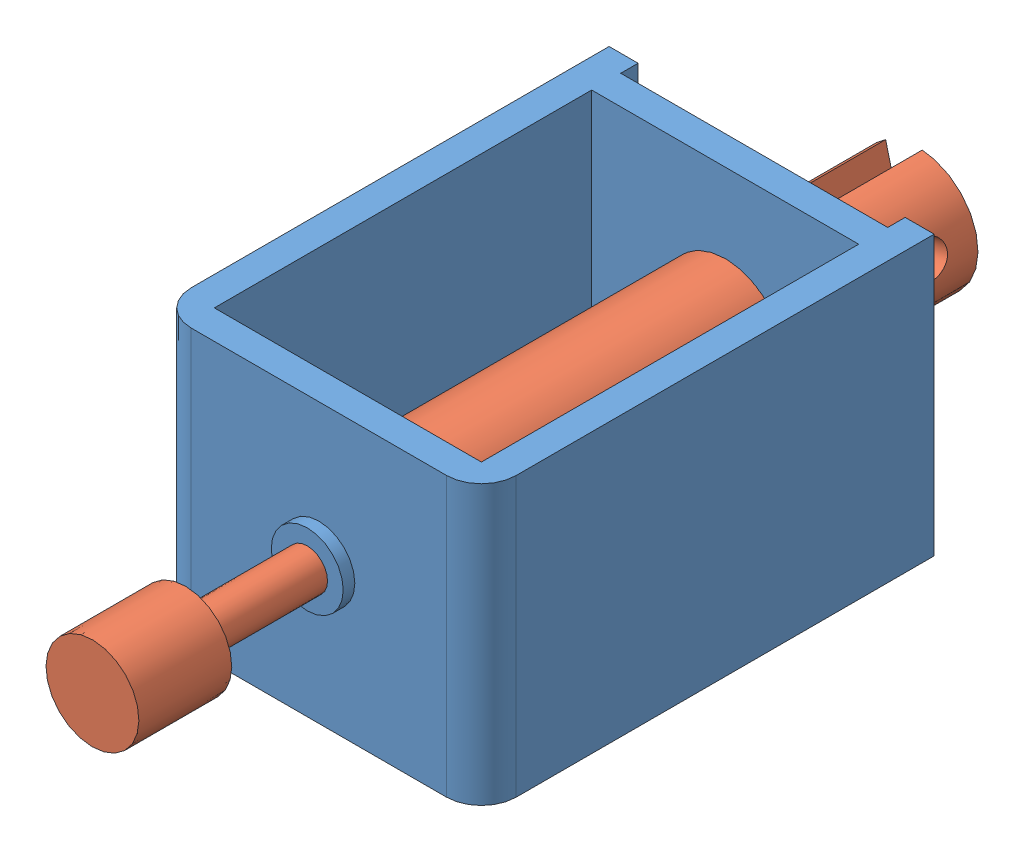
SolidWorks assembly Solenoid, configuration Default. Lengths in mm.
Overall size (28 24 71.1).
2 component instances, 2 part files, 2 mates.
Components (placement in the parent):
- chassis-1: chassis [Default] at (6.2496 23.8466 33.2651) size (28 24 40)
- rod-1: rod [Default] at (20.2496 35.8466 20.6651) x (0 0 1) z (0.969509 0.245056 0) size (71.1 10.35 10.35)
Mates (geometry in assembly coordinates):
- Concentric1: concentric anti-aligned: cylinder of chassis-1 through (20.2496 35.8466 33.2641) axis (0 0 1) radius 1.75; cylinder of rod-1 through (20.2496 35.8466 20.6651) axis (0 0 -1) radius 1.75
- Width1: width aligned: plane of rod-1 through (20.2496 35.8466 69.7651) normal (0 0 1); plane of chassis-1 through (20.2496 35.8466 83.7651) normal (0 0 -1); plane of rod-1 through (8.7496 23.8466 69.7651) normal (0 0 -1); plane of chassis-1 through (6.2496 23.8466 72.2651) normal (0 0 1)
